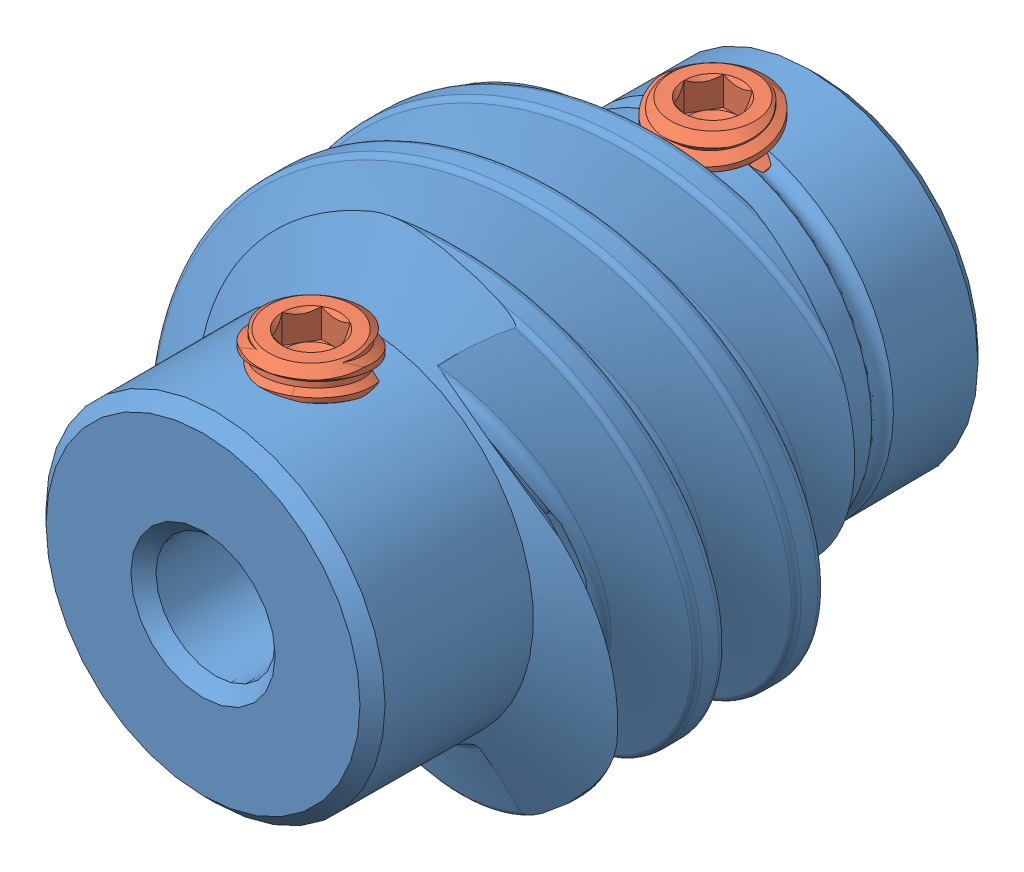
SolidWorks assembly Tetrix Worm Screw (4 to 1), configuration Default. Lengths in mm.
Overall size (33.54 36.22 28.58).
3 component instances, 2 part files, 0 mates.
Components (placement in the parent):
- Tetrix Worm Screw (4 to 1) Body-1: Tetrix Worm Screw (4 to 1) Body [Default] at origin size (33.54 36.22 28.58)
- Tetrix Worm (4 to 1) Set Screw-1: Tetrix Worm (4 to 1) Set Screw [Default] at (0 5.6392 -8.05) x (0.866025 0 -0.5) z (0 1 0) size (4.17 4.24 4.88)
- Tetrix Worm (4 to 1) Set Screw-2: Tetrix Worm (4 to 1) Set Screw [Default] at (0 5.6392 7.95) x (-0.866025 0 0.5) z (0 1 0) size (4.17 4.24 4.88)
